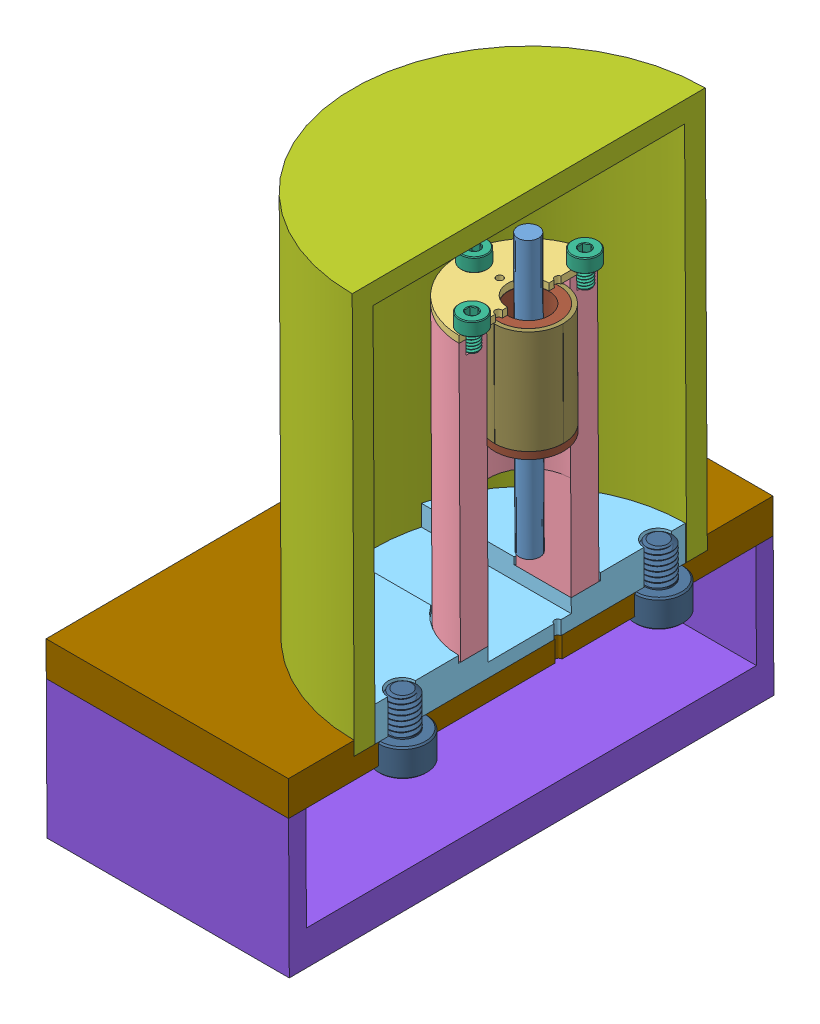
SolidWorks assembly FinalFinal, configuration Default. Lengths in mm.
Overall size (42.01 81.32 70.14).
17 component instances, 12 part files, 21 mates.
Components (placement in the parent):
- Rod-1: Rod [Default] at (-35 35.3478 110.4701) x (-0.020933 -0.005124 0.999768) z (-0.999781 0.000107 -0.020933) size (3 40 3)
- Bearing-7: Bearing [Default] at (-33.9141 58.2749 108.56) x (0 -0.999987 -0.005125) z (-0.999781 0.000107 -0.020933) size (1.6 1.6 1.6)
- Bearing-8: Bearing [Default] at (-37.2061 58.0134 109.9357) x (0 -0.999987 -0.005125) z (-0.999781 0.000107 -0.020933) size (1.6 1.6 1.6)
- Cover2-2: Cover2 [Default] at (-35 67.4339 110.6345) x (-0.019742 -0.005124 0.999792) z (0.999805 -0.000101 0.019742) size (20 1 20)
- 套筒-1: 套筒 [默认] at (-35 26.4344 110.4244) x (-1 0 0) z (0 0.005125 -0.999987) size (20 40 20)
- 底座1-1: 底座1 [默认] at (-35 27.4344 110.4295) x (0 0.005125 -0.999987) z (-1 0 0) size (45 5 45)
- 91290A010_BLACK-OXIDE CLASS 12.9 SOCKET HEAD CAP SCREW-1: 91290A010_BLACK-OXIDE CLASS 12.9 SOCKET HEAD CAP SCREW [91290A010] at (-34.8421 64.4749 102.6208) x (0.999998 0.00001 -0.00203) z (0 -0.999987 -0.005125) size (3.8 3.8 5.09)
- 91290A010_BLACK-OXIDE CLASS 12.9 SOCKET HEAD CAP SCREW-3: 91290A010_BLACK-OXIDE CLASS 12.9 SOCKET HEAD CAP SCREW [91290A010] at (-42.9984 64.4347 110.4612) x (0.999998 0.00001 -0.00203) z (0 -0.999987 -0.005125) size (3.8 3.8 5.09)
- 91290A010_BLACK-OXIDE CLASS 12.9 SOCKET HEAD CAP SCREW-4: 91290A010_BLACK-OXIDE CLASS 12.9 SOCKET HEAD CAP SCREW [91290A010] at (-35.1579 64.3929 118.6175) x (0.999998 0.00001 -0.00203) z (0 -0.999987 -0.005125) size (3.8 3.8 5.09)
- Outer-3: Outer [Default] at (-35.0387 22.4352 110.2651) x (0.990335 -0.000711 0.138693) z (-0.138695 -0.005076 0.990322) size (51 58 51)
- OpAmp-1: OpAmp [Default] at (-113.7592 40.5679 112.1504) x (0 -0.005125 0.999987) z (1 0 0) size (70 28.12 70)
  - Part2-1: Part2 [Default] at (-1.7924 21.1422 78.7206) size (70 20 70)
  - Part1-1: Part1 [Default] at (-1.7924 16.1422 78.7206) size (70 5 70)
  - 91290A138_BLACK-OXIDE CLASS 12.9 SOCKET HEAD CAP SCREW-1: 91290A138_BLACK-OXIDE CLASS 12.9 SOCKET HEAD CAP SCREW [91290A138] at (-20.2924 13.1422 78.7206) x (-0.33762 0 -0.941282) z (0 -1 0) size (7 7 9.29)
  - 91290A138_BLACK-OXIDE CLASS 12.9 SOCKET HEAD CAP SCREW-2: 91290A138_BLACK-OXIDE CLASS 12.9 SOCKET HEAD CAP SCREW [91290A138] at (16.7076 13.1422 78.7206) x (-0.33762 0 -0.941282) z (0 -1 0) size (7 7 9.29)
- MACOR-2: MACOR [Default] at (-34.9374 53.3058 110.6148) x (1 0 0) z (0 0.005125 -0.999987) size (10 16 10)
- PZTFINAL-1: PZTFINAL [Default] at (-34.9374 51.4338 110.6053) x (1 0 0) z (0 -0.005125 0.999987) size (10 15 10)
Mates (geometry in assembly coordinates):
- Tangent9: tangent anti-aligned: cylinder of Rod-1 through (-35 75.3473 110.6751) axis (0 -0.999987 -0.005125) radius 1.5; sphere of Bearing-7
- Lock5: lock: unknown of Rod-1; unknown of Bearing-7
- Tangent11: tangent anti-aligned: cylinder of Rod-1 through (-35 75.3473 110.6751) axis (0 -0.999987 -0.005125) radius 1.5; sphere of Bearing-8
- Lock6: lock: unknown of Rod-1; unknown of Bearing-8
- Concentric15: concentric anti-aligned: cylinder of Cover2-2 through (-35 66.4339 110.6294) axis (0 0.999987 0.005125) radius 10; cylinder of 套筒-1 through (-35 66.4339 110.6294) axis (0 -0.999987 -0.005125) radius 10
- Coincident9: coincident anti-aligned: plane of Cover2-2 through (-35 66.4339 110.6294) normal (0 -0.999987 -0.005125); plane of 套筒-1 through (-35 66.4339 110.6294) normal (0 0.999987 0.005125)
- Concentric16: concentric anti-aligned: circle of Rod-1; circle of Cover2-2
- Coincident10: coincident aligned: plane of 套筒-1 through (-35 26.4344 110.4244) normal (0 -0.999987 -0.005125); circle of 底座1-1
- Concentric17: concentric anti-aligned: circle of 套筒-1; circle of 底座1-1
- Lock8: lock: unknown of Rod-1; unknown of 套筒-1
- Coincident15: coincident anti-aligned: line of 套筒-1 through (-35.0387 26.4652 104.4245) axis (-1 0 0); line of 底座1-1 through (-43.3104 26.4652 104.4245) axis (1 0 0)
- Lock9: lock: unknown of 套筒-1; unknown of 底座1-1
- Coincident20: coincident anti-aligned: plane of Cover2-2 through (-35 67.4339 110.6345) normal (0 0.999987 0.005125); plane of 91290A010_BLACK-OXIDE CLASS 12.9 SOCKET HEAD CAP SCREW-1 through (-34.8421 67.4749 102.6362) normal (0 -0.999987 -0.005125)
- Concentric26: concentric anti-aligned: circle of Cover2-2; circle of 91290A010_BLACK-OXIDE CLASS 12.9 SOCKET HEAD CAP SCREW-1
- Coincident21: coincident anti-aligned: plane of Cover2-2 through (-35 67.4339 110.6345) normal (0 0.999987 0.005125); plane of 91290A010_BLACK-OXIDE CLASS 12.9 SOCKET HEAD CAP SCREW-3 through (-42.9984 67.4347 110.4766) normal (0 -0.999987 -0.005125)
- Coincident22: coincident anti-aligned: plane of Cover2-2 through (-35 67.4339 110.6345) normal (0 0.999987 0.005125); circle of 91290A010_BLACK-OXIDE CLASS 12.9 SOCKET HEAD CAP SCREW-4
- Concentric28: concentric aligned: circle of Cover2-2; circle of 91290A010_BLACK-OXIDE CLASS 12.9 SOCKET HEAD CAP SCREW-3
- Concentric29: concentric anti-aligned: circle of Cover2-2; circle of 91290A010_BLACK-OXIDE CLASS 12.9 SOCKET HEAD CAP SCREW-4
- Concentric30: concentric anti-aligned: cylinder of Outer-3 through (-35.0387 80.4344 110.5623) axis (0 -0.999987 -0.005125) radius 25.5; cylinder of OpAmp-1/Part1-1 through (-35.0387 22.4352 110.2651) axis (0 0.999987 0.005125) radius 25.5
- Coincident25: coincident anti-aligned: plane of Cover2-2 through (-35 66.4339 110.6294) normal (0 -0.999987 -0.005125); plane of PZTFINAL-1 through (-34.9374 66.4336 110.6821) normal (0 0.999987 0.005125)
- Coincident27: coincident anti-aligned: circle of MACOR-2; circle of PZTFINAL-1
